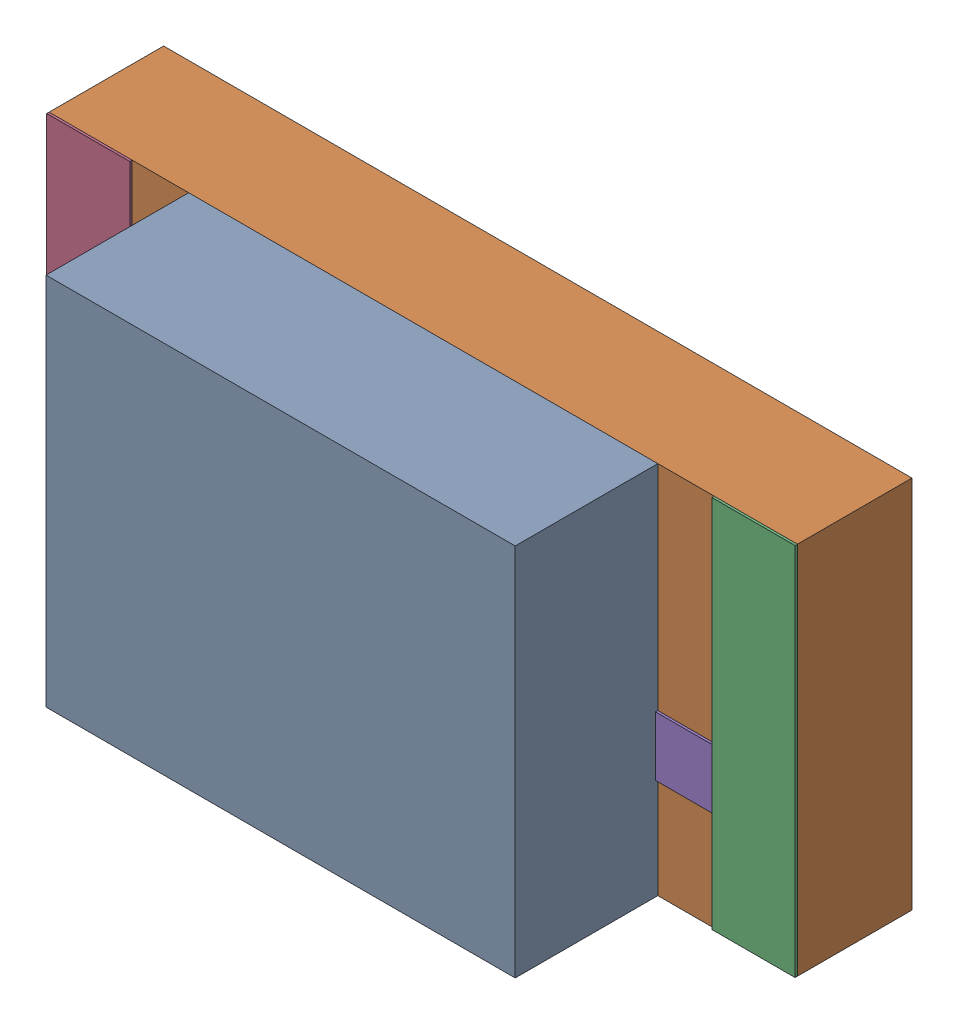
SolidWorks assembly User Library-LED1206R_Open CASCADE STEP translator 6.2 278.2, configuration Default. Lengths in mm.
Overall size (3.2 1.6 1.1).
12 component instances, 5 part files, 0 mates.
Components (placement in the parent):
- User Library-LED1206R_352701008-1: User Library-LED1206R_352701008 [Default] at (1.524 0.0127 0.5027) size (2.01 1.6 0.61)
  - User Library-LED1206R_Extruded2-1: User Library-LED1206R_Extruded2 [Default] at origin size (2.01 1.6 0.61)
- User Library-LED1206R_352697936-1: User Library-LED1206R_352697936 [Default] at (1.524 0.0127 0.0127) size (3.2 1.6 0.49)
  - User Library-LED1206R_Extruded1-1: User Library-LED1206R_Extruded1 [Default] at origin size (3.2 1.6 0.49)
- User Library-LED1206R_352697808-1: User Library-LED1206R_352697808 [Default] at (2.9464 0.0127 0.5027) size (0.36 1.6 0.01)
  - User Library-LED1206R_Extruded-1: User Library-LED1206R_Extruded [Default] at origin size (0.36 1.6 0.01)
- User Library-LED1206R_352697808-2: User Library-LED1206R_352697808 [Default] at (0.1016 0.0127 0.5027) size (0.36 1.6 0.01)
  - User Library-LED1206R_Extruded-1: User Library-LED1206R_Extruded [Default] at origin size (0.36 1.6 0.01)
- User Library-LED1206R_352698192-1: User Library-LED1206R_352698192 [Default] at (2.1971 0.0254 0.5027) size (1.14 0.76 0.01)
  - User Library-LED1206R_Extruded4-1: User Library-LED1206R_Extruded4 [Default] at origin size (1.14 0.76 0.01)
- User Library-LED1206R_352699472-1: User Library-LED1206R_352699472 [Default] at (0.6096 0.0254 0.5027) size (0.65 0.76 0.01)
  - User Library-LED1206R_Extruded3-1: User Library-LED1206R_Extruded3 [Default] at origin size (0.65 0.76 0.01)
